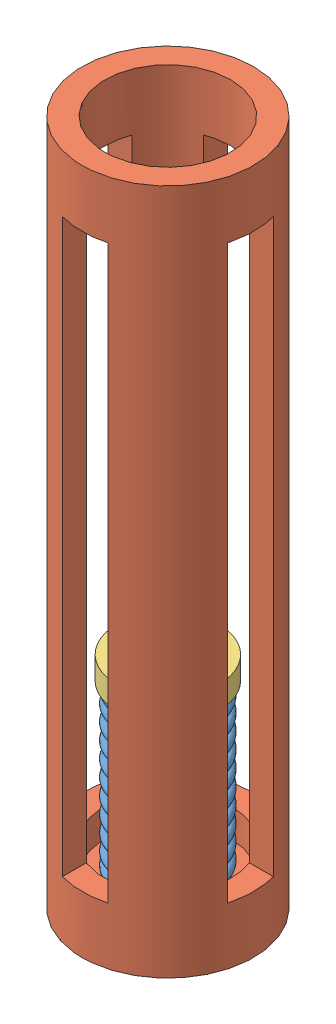
SolidWorks assembly MS-SA-0005 Torpedo Spring Tube 1 inch Claw, configuration Default. Lengths in mm.
Overall size (38.1 152.4 38.1).
3 component instances, 3 part files, 3 mates.
Components (placement in the parent):
- 1986K525_302 STAINLESS STEEL COMPRESSION SPRING-1: 1986K525_302 STAINLESS STEEL COMPRESSION SPRING [1986K525] at (16.8623 -46.4244 245.3297) x (0.437393 0 -0.899271) z (0 -1 0) size (23.69 23.69 38.1)
- MS-P-0089 Torpedo Blank Tube Spring Attachment Claw-1: MS-P-0089 Torpedo Blank Tube Spring Attachment Claw [Default] at (16.8623 -53.7904 245.3297) size (38.1 152.4 38.1)
- MS-P-0090 Torpedo Spring Attachment Claw-1: MS-P-0090 Torpedo Spring Attachment Claw [Default] at (16.8623 -4.9616 245.3297) x (-0.280462 0 0.959865) z (0.959865 0 0.280462) size (22.86 29.46 22.86)
Mates (geometry in assembly coordinates):
- Concentric1: concentric anti-aligned: circle of 1986K525_302 STAINLESS STEEL COMPRESSION SPRING-1; circle of MS-P-0068 Torpedo Blank Tube Spring Attachment-1
- Tangent1: tangent: plane of 1986K525_302 STAINLESS STEEL COMPRESSION SPRING-1; plane of MS-P-0068 Torpedo Blank Tube Spring Attachment Claw-1 through (16.8623 -47.4404 245.3297) normal (0 1 0)
- Concentric2: concentric anti-aligned: circle of MS-P-0089 Torpedo Blank Tube Spring Attachment Claw-1; circle of MS-P-0090 Torpedo Spring Attachment Claw-1
